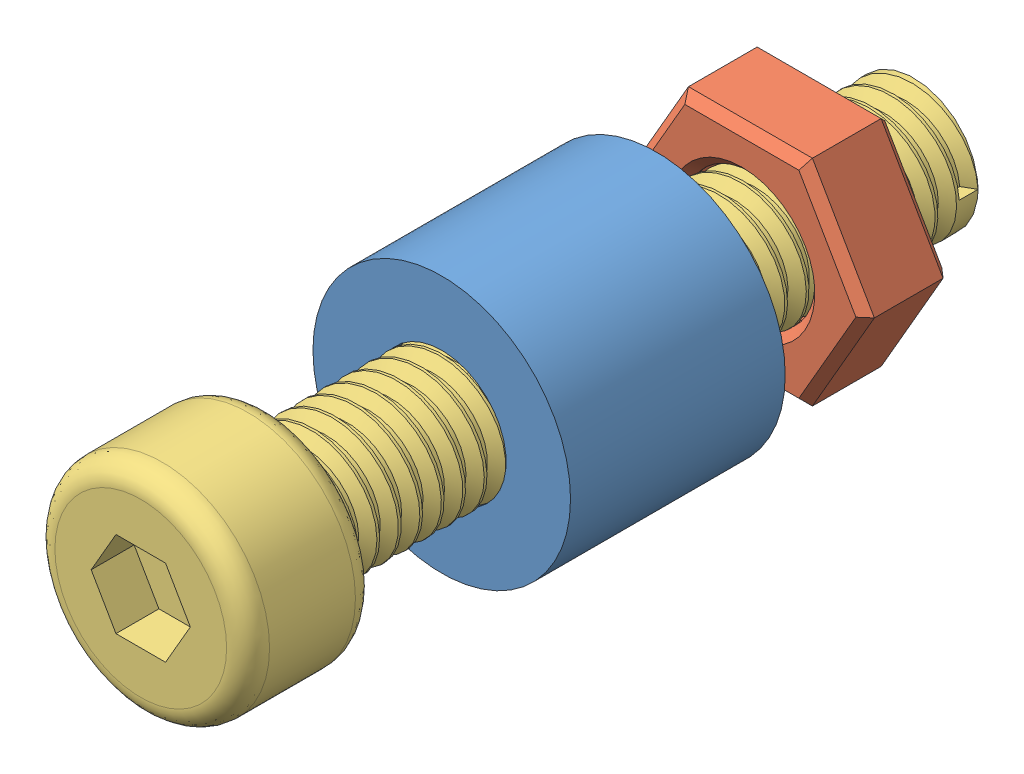
SolidWorks assembly Ajuste Placas, configuration Predeterminado. Lengths in mm.
Overall size (6 6 18).
3 component instances, 3 part files, 4 mates.
Components (placement in the parent):
- Separador 5mm-1: Separador 5mm [Predeterminado] at (-0.4166 -0.05 20.3883) size (6 6 5)
- Tuerca M3-1: Tuerca M3 [Predeterminado] at (-0.4166 -0.05 16.3983) x (1 0 0) z (0 -1 0) size (5.77 2 5)
- Tornillo M3x15_CC-1: Tornillo M3x15_CC [Predeterminado] at (-0.4166 -0.05 14.3983) size (5 5 18)
Mates (geometry in assembly coordinates):
- Distancia2: distance = 1.99 mm anti-aligned: plane of Tuerca M3-1 through (-0.4166 -0.05 18.3983) normal (0 0 1); plane of Separador 5mm-1 through (-0.4166 -0.05 20.3883) normal (0 0 -1)
- Concéntrica1: concentric aligned: circle of Separador 5mm-1; circle of Tuerca M3-1
- Concéntrica2: concentric: cylinder of Separador 5mm-1 through (-0.4166 -0.05 25.3883) axis (0 0 -1) radius 1.5; circle of Tornillo M3x15_CC-1
- Distancia3: distance = 4.01 mm anti-aligned: plane of Tornillo M3x15_CC-1 through (-0.4166 -0.05 29.3983) normal (0 0 -1); plane of Separador 5mm-1 through (-0.4166 -0.05 25.3883) normal (0 0 1)
